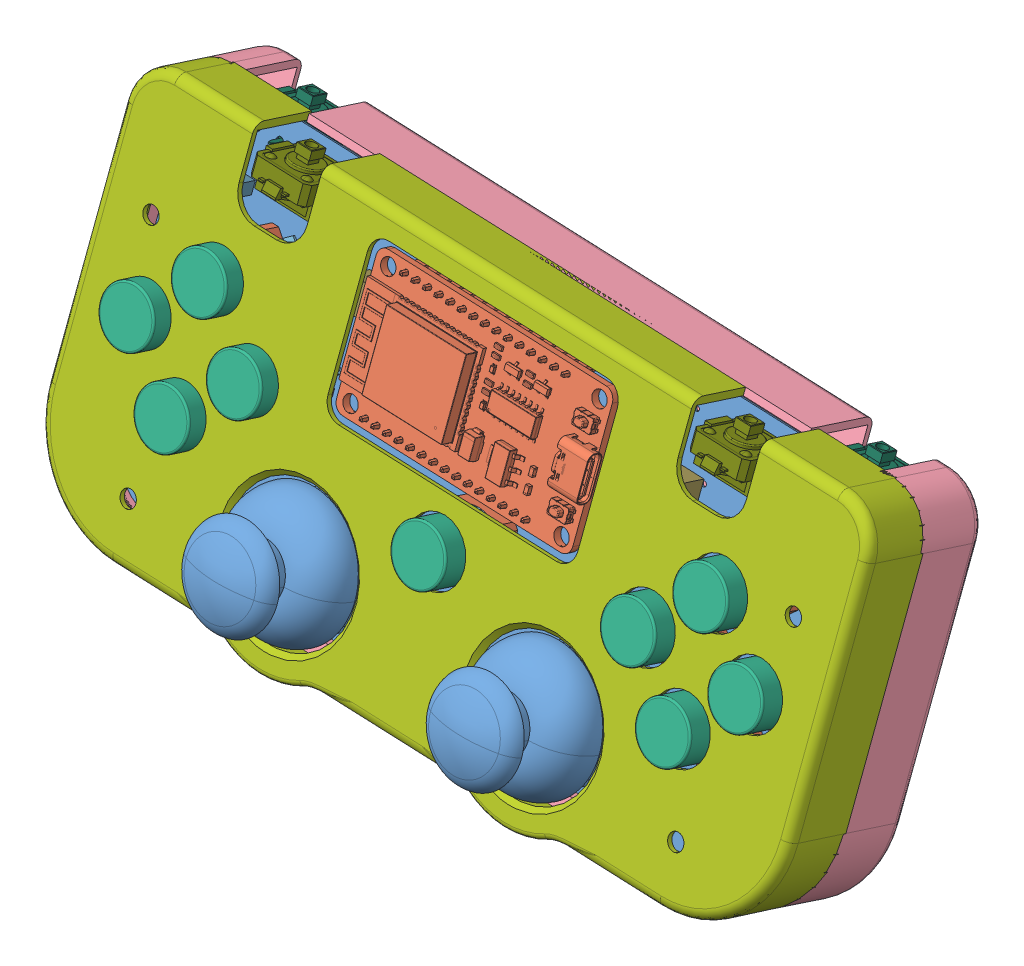
SolidWorks assembly controller, configuration Default. Lengths in mm.
Overall size (166.66 92.08 67.07).
209 component instances, 25 part files, 69 mates.
Components (placement in the parent):
- controller.step-1: controller.step [Default] at (25.4775 3.2443 108.305) x (0.999315 -0.03652 0.006033) z (0.005555 0.30909 0.951017) size (158.62 75.66 29.81)
  - Board.step-1: Board.step [Default] at origin size (158.62 74.17 0.41)
    - Open CASCADE STEP translator 7.5 1.1.1.step-1: Open CASCADE STEP translator 7.5 1.1.1.step [Default] at (0 0 -0.4115) size (158.62 74.17 0.41)
  - SW11.step-1: SW11.step [Default] at origin size (12 13.8 8.01)
    - Switch_Omron_B3F-4000_eec.step-1: Switch_Omron_B3F-4000_eec.step [Default] at (92.7295 35.2468 2.4624) x (0 1 0) z (0 0 1) size (13.8 12 8.01)
      - Omron B3F-4000 1.step-1: Omron B3F-4000 1.step [Default] at (3.1026 -5.4513 -0.4613) size (12 12 5.5)
      - Omron B3F-4000 2.step-1: Omron B3F-4000 2.step [Default] at (3.1026 -5.4513 2.5387) x (-1 0 0) z (0 0 1) size (11 11 0.5)
      - Omron B3F-4000 3.step-1: Omron B3F-4000 3.step [Default] at (3.1026 -5.4513 4.0387) x (1 0 0) z (0 0 -1) size (7.1 7.1 1.5)
      - Omron B3F-4000 4.step-1: Omron B3F-4000 4.step [Default] at (9.5526 -2.4513 -1.9613) x (1 0 0) z (0 -1 0) size (0.9 4 1)
      - Omron B3F-4000 4.step-2: Omron B3F-4000 4.step [Default] at (9.5526 -7.4513 -1.9613) x (1 0 0) z (0 -1 0) size (0.9 4 1)
      - Omron B3F-4000 4_MIR.step-1: Omron B3F-4000 4_MIR.step [Default] at (-3.3474 -2.4513 -1.9613) x (-1 0 0) z (0 1 0) size (0.9 4 1)
      - Omron B3F-4000 4_MIR.step-2: Omron B3F-4000 4_MIR.step [Default] at (-3.3474 -7.4513 -1.9613) x (-1 0 0) z (0 1 0) size (0.9 4 1)
      - Omron B3F-4000 5.step-1: Omron B3F-4000 5.step [Default] at (7.6026 -0.9513 3.0387) size (1.5 1.5 1.2)
      - Omron B3F-4000 5_MIR2.step-1: Omron B3F-4000 5_MIR2.step [Default] at (7.6026 -9.9513 3.0387) x (1 0 0) z (0 0 -1) size (1.5 1.5 1.2)
      - Omron B3F-4000 5_MIR3.step-1: Omron B3F-4000 5_MIR3.step [Default] at (-1.3974 -0.9513 3.0387) x (-1 0 0) z (0 0 -1) size (1.5 1.5 1.2)
      - Omron B3F-4000 5_MIR2_MIR.step-1: Omron B3F-4000 5_MIR2_MIR.step [Default] at (-1.3974 -9.9513 3.0387) x (-1 0 0) z (0 0 1) size (1.5 1.5 1.2)
      - Omron.step-1: Omron.step [Default] at (3.0502 -5.7952 4.0387) size (2.99 0.61 0.02)
  - SW9.step-1: SW9.step [Default] at origin size (6 6 4.5)
    - 7098939168.step-1: 7098939168.step [Default] at (64.389 64.262 0) size (6 6 4.5)
      - Extruded.step-1: Extruded.step [Default] at origin size (6 6 4.5)
  - SW10.step-1: SW10.step [Default] at origin size (6 6 4.5)
    - 7098939168.step-1: 7098939168.step [Default] at (131.953 64.262 0) size (6 6 4.5)
      - Extruded.step-1: Extruded.step [Default] at origin size (6 6 4.5)
  - C5.step-1: C5.step [Default] at origin size (3.81 2.54 11.66)
    - 7094425376.step-1: 7094425376.step [Default] at (34.6711 68.58 -7) size (0.51 0.51 7)
      - Extruded-0.step-1: Extruded-0.step [Default] at origin size (0.51 0.51 7)
    - 7094425376.step-2: 7094425376.step [Default] at (32.1311 68.5801 -7) size (0.51 0.51 7)
      - Extruded-0.step-1: Extruded-0.step [Default] at origin size (0.51 0.51 7)
    - 7098940608.step-1: 7098940608.step [Default] at (33.401 68.58 0) size (3.81 2.54 4.66)
      - Extruded-1.step-1: Extruded-1.step [Default] at origin size (3.81 2.54 4.66)
  - C6.step-1: C6.step [Default] at origin size (3.81 2.54 11.66)
    - 7094425376.step-1: 7094425376.step [Default] at (165.3541 67.31 -7) size (0.51 0.51 7)
      - Extruded-0.step-1: Extruded-0.step [Default] at origin size (0.51 0.51 7)
    - 7094425376.step-2: 7094425376.step [Default] at (162.8141 67.3101 -7) size (0.51 0.51 7)
      - Extruded-0.step-1: Extruded-0.step [Default] at origin size (0.51 0.51 7)
    - 7098940608.step-1: 7098940608.step [Default] at (164.084 67.31 0) size (3.81 2.54 4.66)
      - Extruded-1.step-1: Extruded-1.step [Default] at origin size (3.81 2.54 4.66)
  - S4.step-1: S4.step [Default] at origin size (13.1 13.3 18.3)
    - 6508629744.step-1: 6508629744.step [Default] at (160.742 77.978 -0.4115) x (0 -1 0) z (1 0 0) size (13.3 18.3 13.1)
  - S3.step-1: S3.step [Default] at origin size (13.1 13.3 18.3)
    - 6508631584.step-1: 6508631584.step [Default] at (146.344 77.978 0) x (0 -1 0) z (-1 0 0) size (13.3 18.3 13.1)
  - S2.step-1: S2.step [Default] at origin size (13.1 13.3 18.3)
    - 6508631584.step-1: 6508631584.step [Default] at (49.744 77.978 0) x (0 -1 0) z (-1 0 0) size (13.3 18.3 13.1)
  - S1.step-1: S1.step [Default] at origin size (13.1 13.3 18.3)
    - 6508629744.step-1: 6508629744.step [Default] at (35.346 77.978 -0.4115) x (0 -1 0) z (1 0 0) size (13.3 18.3 13.1)
  - C4.step-1: C4.step [Default] at origin size (4.49 4.49 11.66)
    - 7094425376.step-1: 7094425376.step [Default] at (30.4371 33.138 -7) size (0.51 0.51 7)
      - Extruded-0.step-1: Extruded-0.step [Default] at origin size (0.51 0.51 7)
    - 7094425376.step-2: 7094425376.step [Default] at (28.6411 34.9341 -7) size (0.51 0.51 7)
      - Extruded-0.step-1: Extruded-0.step [Default] at origin size (0.51 0.51 7)
    - 7094424896.step-1: 7094424896.step [Default] at (29.5392 34.036 0) size (4.49 4.49 4.66)
      - Extruded-2.step-1: Extruded-2.step [Default] at origin size (4.49 4.49 4.66)
  - C3.step-1: C3.step [Default] at origin size (4.49 4.49 11.66)
    - 7094425376.step-1: 7094425376.step [Default] at (166.7082 33.9179 -7) size (0.51 0.51 7)
      - Extruded-0.step-1: Extruded-0.step [Default] at origin size (0.51 0.51 7)
    - 7094425376.step-2: 7094425376.step [Default] at (164.9122 32.1219 -7) size (0.51 0.51 7)
      - Extruded-0.step-1: Extruded-0.step [Default] at origin size (0.51 0.51 7)
    - 7098938768.step-1: 7098938768.step [Default] at (165.8102 33.02 0) size (4.49 4.49 4.66)
      - Extruded-3.step-1: Extruded-3.step [Default] at origin size (4.49 4.49 4.66)
  - C2.step-1: C2.step [Default] at origin size (4.49 4.49 11.66)
    - 7094425376.step-1: 7094425376.step [Default] at (55.4293 60.9781 -7) size (0.51 0.51 7)
      - Extruded-0.step-1: Extruded-0.step [Default] at origin size (0.51 0.51 7)
    - 7094425376.step-2: 7094425376.step [Default] at (57.2253 59.182 -7) size (0.51 0.51 7)
      - Extruded-0.step-1: Extruded-0.step [Default] at origin size (0.51 0.51 7)
    - 7094424896.step-1: 7094424896.step [Default] at (56.3272 60.08 0) size (4.49 4.49 4.66)
      - Extruded-2.step-1: Extruded-2.step [Default] at origin size (4.49 4.49 4.66)
  - C1.step-1: C1.step [Default] at origin size (4.49 4.49 11.66)
    - 7094425376.step-1: 7094425376.step [Default] at (139.5122 58.4111 -7) size (0.51 0.51 7)
      - Extruded-0.step-1: Extruded-0.step [Default] at origin size (0.51 0.51 7)
    - 7094425376.step-2: 7094425376.step [Default] at (141.3083 60.2071 -7) size (0.51 0.51 7)
      - Extruded-0.step-1: Extruded-0.step [Default] at origin size (0.51 0.51 7)
    - 7098938768.step-1: 7098938768.step [Default] at (140.4102 59.309 0) size (4.49 4.49 4.66)
      - Extruded-3.step-1: Extruded-3.step [Default] at origin size (4.49 4.49 4.66)
  - SW1.step-1: SW1.step [Default] at origin size (18.24 18.24 8.01)
    - Switch_Omron_B3F-4000_eec.step-1: Switch_Omron_B3F-4000_eec.step [Default] at (48.6404 48.2596 2.4624) x (0.707107 0.707107 0) z (0 0 1) size (13.8 12 8.01)
      - Omron B3F-4000 1.step-1: Omron B3F-4000 1.step [Default] at (3.1026 -5.4513 -0.4613) size (12 12 5.5)
      - Omron B3F-4000 2.step-1: Omron B3F-4000 2.step [Default] at (3.1026 -5.4513 2.5387) x (-1 0 0) z (0 0 1) size (11 11 0.5)
      - Omron B3F-4000 3.step-1: Omron B3F-4000 3.step [Default] at (3.1026 -5.4513 4.0387) x (1 0 0) z (0 0 -1) size (7.1 7.1 1.5)
      - Omron B3F-4000 4.step-1: Omron B3F-4000 4.step [Default] at (9.5526 -2.4513 -1.9613) x (1 0 0) z (0 -1 0) size (0.9 4 1)
      - Omron B3F-4000 4.step-2: Omron B3F-4000 4.step [Default] at (9.5526 -7.4513 -1.9613) x (1 0 0) z (0 -1 0) size (0.9 4 1)
      - Omron B3F-4000 4_MIR.step-1: Omron B3F-4000 4_MIR.step [Default] at (-3.3474 -2.4513 -1.9613) x (-1 0 0) z (0 1 0) size (0.9 4 1)
      - Omron B3F-4000 4_MIR.step-2: Omron B3F-4000 4_MIR.step [Default] at (-3.3474 -7.4513 -1.9613) x (-1 0 0) z (0 1 0) size (0.9 4 1)
      - Omron B3F-4000 5.step-1: Omron B3F-4000 5.step [Default] at (7.6026 -0.9513 3.0387) size (1.5 1.5 1.2)
      - Omron B3F-4000 5_MIR2.step-1: Omron B3F-4000 5_MIR2.step [Default] at (7.6026 -9.9513 3.0387) x (1 0 0) z (0 0 -1) size (1.5 1.5 1.2)
      - Omron B3F-4000 5_MIR3.step-1: Omron B3F-4000 5_MIR3.step [Default] at (-1.3974 -0.9513 3.0387) x (-1 0 0) z (0 0 -1) size (1.5 1.5 1.2)
      - Omron B3F-4000 5_MIR2_MIR.step-1: Omron B3F-4000 5_MIR2_MIR.step [Default] at (-1.3974 -9.9513 3.0387) x (-1 0 0) z (0 0 1) size (1.5 1.5 1.2)
      - Omron.step-1: Omron.step [Default] at (3.0502 -5.7952 4.0387) size (2.99 0.61 0.02)
  - SW2.step-1: SW2.step [Default] at origin size (18.24 18.24 8.01)
    - Switch_Omron_B3F-4000_eec.step-1: Switch_Omron_B3F-4000_eec.step [Default] at (36.8294 60.0706 2.4624) x (0.707107 0.707107 0) z (0 0 1) size (13.8 12 8.01)
      - Omron B3F-4000 1.step-1: Omron B3F-4000 1.step [Default] at (3.1026 -5.4513 -0.4613) size (12 12 5.5)
      - Omron B3F-4000 2.step-1: Omron B3F-4000 2.step [Default] at (3.1026 -5.4513 2.5387) x (-1 0 0) z (0 0 1) size (11 11 0.5)
      - Omron B3F-4000 3.step-1: Omron B3F-4000 3.step [Default] at (3.1026 -5.4513 4.0387) x (1 0 0) z (0 0 -1) size (7.1 7.1 1.5)
      - Omron B3F-4000 4.step-1: Omron B3F-4000 4.step [Default] at (9.5526 -2.4513 -1.9613) x (1 0 0) z (0 -1 0) size (0.9 4 1)
      - Omron B3F-4000 4.step-2: Omron B3F-4000 4.step [Default] at (9.5526 -7.4513 -1.9613) x (1 0 0) z (0 -1 0) size (0.9 4 1)
      - Omron B3F-4000 4_MIR.step-1: Omron B3F-4000 4_MIR.step [Default] at (-3.3474 -2.4513 -1.9613) x (-1 0 0) z (0 1 0) size (0.9 4 1)
      - Omron B3F-4000 4_MIR.step-2: Omron B3F-4000 4_MIR.step [Default] at (-3.3474 -7.4513 -1.9613) x (-1 0 0) z (0 1 0) size (0.9 4 1)
      - Omron B3F-4000 5.step-1: Omron B3F-4000 5.step [Default] at (7.6026 -0.9513 3.0387) size (1.5 1.5 1.2)
      - Omron B3F-4000 5_MIR2.step-1: Omron B3F-4000 5_MIR2.step [Default] at (7.6026 -9.9513 3.0387) x (1 0 0) z (0 0 -1) size (1.5 1.5 1.2)
      - Omron B3F-4000 5_MIR3.step-1: Omron B3F-4000 5_MIR3.step [Default] at (-1.3974 -0.9513 3.0387) x (-1 0 0) z (0 0 -1) size (1.5 1.5 1.2)
      - Omron B3F-4000 5_MIR2_MIR.step-1: Omron B3F-4000 5_MIR2_MIR.step [Default] at (-1.3974 -9.9513 3.0387) x (-1 0 0) z (0 0 1) size (1.5 1.5 1.2)
      - Omron.step-1: Omron.step [Default] at (3.0502 -5.7952 4.0387) size (2.99 0.61 0.02)
  - SW3.step-1: SW3.step [Default] at origin size (18.24 18.24 8.01)
    - Switch_Omron_B3F-4000_eec.step-1: Switch_Omron_B3F-4000_eec.step [Default] at (25.0184 48.2596 2.4624) x (0.707107 0.707107 0) z (0 0 1) size (13.8 12 8.01)
      - Omron B3F-4000 1.step-1: Omron B3F-4000 1.step [Default] at (3.1026 -5.4513 -0.4613) size (12 12 5.5)
      - Omron B3F-4000 2.step-1: Omron B3F-4000 2.step [Default] at (3.1026 -5.4513 2.5387) x (-1 0 0) z (0 0 1) size (11 11 0.5)
      - Omron B3F-4000 3.step-1: Omron B3F-4000 3.step [Default] at (3.1026 -5.4513 4.0387) x (1 0 0) z (0 0 -1) size (7.1 7.1 1.5)
      - Omron B3F-4000 4.step-1: Omron B3F-4000 4.step [Default] at (9.5526 -2.4513 -1.9613) x (1 0 0) z (0 -1 0) size (0.9 4 1)
      - Omron B3F-4000 4.step-2: Omron B3F-4000 4.step [Default] at (9.5526 -7.4513 -1.9613) x (1 0 0) z (0 -1 0) size (0.9 4 1)
      - Omron B3F-4000 4_MIR.step-1: Omron B3F-4000 4_MIR.step [Default] at (-3.3474 -2.4513 -1.9613) x (-1 0 0) z (0 1 0) size (0.9 4 1)
      - Omron B3F-4000 4_MIR.step-2: Omron B3F-4000 4_MIR.step [Default] at (-3.3474 -7.4513 -1.9613) x (-1 0 0) z (0 1 0) size (0.9 4 1)
      - Omron B3F-4000 5.step-1: Omron B3F-4000 5.step [Default] at (7.6026 -0.9513 3.0387) size (1.5 1.5 1.2)
      - Omron B3F-4000 5_MIR2.step-1: Omron B3F-4000 5_MIR2.step [Default] at (7.6026 -9.9513 3.0387) x (1 0 0) z (0 0 -1) size (1.5 1.5 1.2)
      - Omron B3F-4000 5_MIR3.step-1: Omron B3F-4000 5_MIR3.step [Default] at (-1.3974 -0.9513 3.0387) x (-1 0 0) z (0 0 -1) size (1.5 1.5 1.2)
      - Omron B3F-4000 5_MIR2_MIR.step-1: Omron B3F-4000 5_MIR2_MIR.step [Default] at (-1.3974 -9.9513 3.0387) x (-1 0 0) z (0 0 1) size (1.5 1.5 1.2)
      - Omron.step-1: Omron.step [Default] at (3.0502 -5.7952 4.0387) size (2.99 0.61 0.02)
  - SW4.step-1: SW4.step [Default] at origin size (18.24 18.24 8.01)
    - Switch_Omron_B3F-4000_eec.step-1: Switch_Omron_B3F-4000_eec.step [Default] at (36.8294 36.4486 2.4624) x (0.707107 0.707107 0) z (0 0 1) size (13.8 12 8.01)
      - Omron B3F-4000 1.step-1: Omron B3F-4000 1.step [Default] at (3.1026 -5.4513 -0.4613) size (12 12 5.5)
      - Omron B3F-4000 2.step-1: Omron B3F-4000 2.step [Default] at (3.1026 -5.4513 2.5387) x (-1 0 0) z (0 0 1) size (11 11 0.5)
      - Omron B3F-4000 3.step-1: Omron B3F-4000 3.step [Default] at (3.1026 -5.4513 4.0387) x (1 0 0) z (0 0 -1) size (7.1 7.1 1.5)
      - Omron B3F-4000 4.step-1: Omron B3F-4000 4.step [Default] at (9.5526 -2.4513 -1.9613) x (1 0 0) z (0 -1 0) size (0.9 4 1)
      - Omron B3F-4000 4.step-2: Omron B3F-4000 4.step [Default] at (9.5526 -7.4513 -1.9613) x (1 0 0) z (0 -1 0) size (0.9 4 1)
      - Omron B3F-4000 4_MIR.step-1: Omron B3F-4000 4_MIR.step [Default] at (-3.3474 -2.4513 -1.9613) x (-1 0 0) z (0 1 0) size (0.9 4 1)
      - Omron B3F-4000 4_MIR.step-2: Omron B3F-4000 4_MIR.step [Default] at (-3.3474 -7.4513 -1.9613) x (-1 0 0) z (0 1 0) size (0.9 4 1)
      - Omron B3F-4000 5.step-1: Omron B3F-4000 5.step [Default] at (7.6026 -0.9513 3.0387) size (1.5 1.5 1.2)
      - Omron B3F-4000 5_MIR2.step-1: Omron B3F-4000 5_MIR2.step [Default] at (7.6026 -9.9513 3.0387) x (1 0 0) z (0 0 -1) size (1.5 1.5 1.2)
      - Omron B3F-4000 5_MIR3.step-1: Omron B3F-4000 5_MIR3.step [Default] at (-1.3974 -0.9513 3.0387) x (-1 0 0) z (0 0 -1) size (1.5 1.5 1.2)
      - Omron B3F-4000 5_MIR2_MIR.step-1: Omron B3F-4000 5_MIR2_MIR.step [Default] at (-1.3974 -9.9513 3.0387) x (-1 0 0) z (0 0 1) size (1.5 1.5 1.2)
      - Omron.step-1: Omron.step [Default] at (3.0502 -5.7952 4.0387) size (2.99 0.61 0.02)
  - SW8.step-1: SW8.step [Default] at origin size (18.24 18.24 8.01)
    - Switch_Omron_B3F-4000_eec.step-1: Switch_Omron_B3F-4000_eec.step [Default] at (147.1924 36.4486 2.4624) x (0.707107 0.707107 0) z (0 0 1) size (13.8 12 8.01)
      - Omron B3F-4000 1.step-1: Omron B3F-4000 1.step [Default] at (3.1026 -5.4513 -0.4613) size (12 12 5.5)
      - Omron B3F-4000 2.step-1: Omron B3F-4000 2.step [Default] at (3.1026 -5.4513 2.5387) x (-1 0 0) z (0 0 1) size (11 11 0.5)
      - Omron B3F-4000 3.step-1: Omron B3F-4000 3.step [Default] at (3.1026 -5.4513 4.0387) x (1 0 0) z (0 0 -1) size (7.1 7.1 1.5)
      - Omron B3F-4000 4.step-1: Omron B3F-4000 4.step [Default] at (9.5526 -2.4513 -1.9613) x (1 0 0) z (0 -1 0) size (0.9 4 1)
      - Omron B3F-4000 4.step-2: Omron B3F-4000 4.step [Default] at (9.5526 -7.4513 -1.9613) x (1 0 0) z (0 -1 0) size (0.9 4 1)
      - Omron B3F-4000 4_MIR.step-1: Omron B3F-4000 4_MIR.step [Default] at (-3.3474 -2.4513 -1.9613) x (-1 0 0) z (0 1 0) size (0.9 4 1)
      - Omron B3F-4000 4_MIR.step-2: Omron B3F-4000 4_MIR.step [Default] at (-3.3474 -7.4513 -1.9613) x (-1 0 0) z (0 1 0) size (0.9 4 1)
      - Omron B3F-4000 5.step-1: Omron B3F-4000 5.step [Default] at (7.6026 -0.9513 3.0387) size (1.5 1.5 1.2)
      - Omron B3F-4000 5_MIR2.step-1: Omron B3F-4000 5_MIR2.step [Default] at (7.6026 -9.9513 3.0387) x (1 0 0) z (0 0 -1) size (1.5 1.5 1.2)
      - Omron B3F-4000 5_MIR3.step-1: Omron B3F-4000 5_MIR3.step [Default] at (-1.3974 -0.9513 3.0387) x (-1 0 0) z (0 0 -1) size (1.5 1.5 1.2)
      - Omron B3F-4000 5_MIR2_MIR.step-1: Omron B3F-4000 5_MIR2_MIR.step [Default] at (-1.3974 -9.9513 3.0387) x (-1 0 0) z (0 0 1) size (1.5 1.5 1.2)
      - Omron.step-1: Omron.step [Default] at (3.0502 -5.7952 4.0387) size (2.99 0.61 0.02)
  - SW7.step-1: SW7.step [Default] at origin size (18.24 18.24 8.01)
    - Switch_Omron_B3F-4000_eec.step-1: Switch_Omron_B3F-4000_eec.step [Default] at (135.3813 48.2596 2.4624) x (0.707107 0.707107 0) z (0 0 1) size (13.8 12 8.01)
      - Omron B3F-4000 1.step-1: Omron B3F-4000 1.step [Default] at (3.1026 -5.4513 -0.4613) size (12 12 5.5)
      - Omron B3F-4000 2.step-1: Omron B3F-4000 2.step [Default] at (3.1026 -5.4513 2.5387) x (-1 0 0) z (0 0 1) size (11 11 0.5)
      - Omron B3F-4000 3.step-1: Omron B3F-4000 3.step [Default] at (3.1026 -5.4513 4.0387) x (1 0 0) z (0 0 -1) size (7.1 7.1 1.5)
      - Omron B3F-4000 4.step-1: Omron B3F-4000 4.step [Default] at (9.5526 -2.4513 -1.9613) x (1 0 0) z (0 -1 0) size (0.9 4 1)
      - Omron B3F-4000 4.step-2: Omron B3F-4000 4.step [Default] at (9.5526 -7.4513 -1.9613) x (1 0 0) z (0 -1 0) size (0.9 4 1)
      - Omron B3F-4000 4_MIR.step-1: Omron B3F-4000 4_MIR.step [Default] at (-3.3474 -2.4513 -1.9613) x (-1 0 0) z (0 1 0) size (0.9 4 1)
      - Omron B3F-4000 4_MIR.step-2: Omron B3F-4000 4_MIR.step [Default] at (-3.3474 -7.4513 -1.9613) x (-1 0 0) z (0 1 0) size (0.9 4 1)
      - Omron B3F-4000 5.step-1: Omron B3F-4000 5.step [Default] at (7.6026 -0.9513 3.0387) size (1.5 1.5 1.2)
      - Omron B3F-4000 5_MIR2.step-1: Omron B3F-4000 5_MIR2.step [Default] at (7.6026 -9.9513 3.0387) x (1 0 0) z (0 0 -1) size (1.5 1.5 1.2)
      - Omron B3F-4000 5_MIR3.step-1: Omron B3F-4000 5_MIR3.step [Default] at (-1.3974 -0.9513 3.0387) x (-1 0 0) z (0 0 -1) size (1.5 1.5 1.2)
      - Omron B3F-4000 5_MIR2_MIR.step-1: Omron B3F-4000 5_MIR2_MIR.step [Default] at (-1.3974 -9.9513 3.0387) x (-1 0 0) z (0 0 1) size (1.5 1.5 1.2)
      - Omron.step-1: Omron.step [Default] at (3.0502 -5.7952 4.0387) size (2.99 0.61 0.02)
  - SW6.step-1: SW6.step [Default] at origin size (18.24 18.24 8.01)
    - Switch_Omron_B3F-4000_eec.step-1: Switch_Omron_B3F-4000_eec.step [Default] at (147.1924 60.0706 2.4624) x (0.707107 0.707107 0) z (0 0 1) size (13.8 12 8.01)
      - Omron B3F-4000 1.step-1: Omron B3F-4000 1.step [Default] at (3.1026 -5.4513 -0.4613) size (12 12 5.5)
      - Omron B3F-4000 2.step-1: Omron B3F-4000 2.step [Default] at (3.1026 -5.4513 2.5387) x (-1 0 0) z (0 0 1) size (11 11 0.5)
      - Omron B3F-4000 3.step-1: Omron B3F-4000 3.step [Default] at (3.1026 -5.4513 4.0387) x (1 0 0) z (0 0 -1) size (7.1 7.1 1.5)
      - Omron B3F-4000 4.step-1: Omron B3F-4000 4.step [Default] at (9.5526 -2.4513 -1.9613) x (1 0 0) z (0 -1 0) size (0.9 4 1)
      - Omron B3F-4000 4.step-2: Omron B3F-4000 4.step [Default] at (9.5526 -7.4513 -1.9613) x (1 0 0) z (0 -1 0) size (0.9 4 1)
      - Omron B3F-4000 4_MIR.step-1: Omron B3F-4000 4_MIR.step [Default] at (-3.3474 -2.4513 -1.9613) x (-1 0 0) z (0 1 0) size (0.9 4 1)
      - Omron B3F-4000 4_MIR.step-2: Omron B3F-4000 4_MIR.step [Default] at (-3.3474 -7.4513 -1.9613) x (-1 0 0) z (0 1 0) size (0.9 4 1)
      - Omron B3F-4000 5.step-1: Omron B3F-4000 5.step [Default] at (7.6026 -0.9513 3.0387) size (1.5 1.5 1.2)
      - Omron B3F-4000 5_MIR2.step-1: Omron B3F-4000 5_MIR2.step [Default] at (7.6026 -9.9513 3.0387) x (1 0 0) z (0 0 -1) size (1.5 1.5 1.2)
      - Omron B3F-4000 5_MIR3.step-1: Omron B3F-4000 5_MIR3.step [Default] at (-1.3974 -0.9513 3.0387) x (-1 0 0) z (0 0 -1) size (1.5 1.5 1.2)
      - Omron B3F-4000 5_MIR2_MIR.step-1: Omron B3F-4000 5_MIR2_MIR.step [Default] at (-1.3974 -9.9513 3.0387) x (-1 0 0) z (0 0 1) size (1.5 1.5 1.2)
      - Omron.step-1: Omron.step [Default] at (3.0502 -5.7952 4.0387) size (2.99 0.61 0.02)
  - SW5.step-1: SW5.step [Default] at origin size (18.24 18.24 8.01)
    - Switch_Omron_B3F-4000_eec.step-1: Switch_Omron_B3F-4000_eec.step [Default] at (159.0034 48.2596 2.4624) x (0.707107 0.707107 0) z (0 0 1) size (13.8 12 8.01)
      - Omron B3F-4000 1.step-1: Omron B3F-4000 1.step [Default] at (3.1026 -5.4513 -0.4613) size (12 12 5.5)
      - Omron B3F-4000 2.step-1: Omron B3F-4000 2.step [Default] at (3.1026 -5.4513 2.5387) x (-1 0 0) z (0 0 1) size (11 11 0.5)
      - Omron B3F-4000 3.step-1: Omron B3F-4000 3.step [Default] at (3.1026 -5.4513 4.0387) x (1 0 0) z (0 0 -1) size (7.1 7.1 1.5)
      - Omron B3F-4000 4.step-1: Omron B3F-4000 4.step [Default] at (9.5526 -2.4513 -1.9613) x (1 0 0) z (0 -1 0) size (0.9 4 1)
      - Omron B3F-4000 4.step-2: Omron B3F-4000 4.step [Default] at (9.5526 -7.4513 -1.9613) x (1 0 0) z (0 -1 0) size (0.9 4 1)
      - Omron B3F-4000 4_MIR.step-1: Omron B3F-4000 4_MIR.step [Default] at (-3.3474 -2.4513 -1.9613) x (-1 0 0) z (0 1 0) size (0.9 4 1)
      - Omron B3F-4000 4_MIR.step-2: Omron B3F-4000 4_MIR.step [Default] at (-3.3474 -7.4513 -1.9613) x (-1 0 0) z (0 1 0) size (0.9 4 1)
      - Omron B3F-4000 5.step-1: Omron B3F-4000 5.step [Default] at (7.6026 -0.9513 3.0387) size (1.5 1.5 1.2)
      - Omron B3F-4000 5_MIR2.step-1: Omron B3F-4000 5_MIR2.step [Default] at (7.6026 -9.9513 3.0387) x (1 0 0) z (0 0 -1) size (1.5 1.5 1.2)
      - Omron B3F-4000 5_MIR3.step-1: Omron B3F-4000 5_MIR3.step [Default] at (-1.3974 -0.9513 3.0387) x (-1 0 0) z (0 0 -1) size (1.5 1.5 1.2)
      - Omron B3F-4000 5_MIR2_MIR.step-1: Omron B3F-4000 5_MIR2_MIR.step [Default] at (-1.3974 -9.9513 3.0387) x (-1 0 0) z (0 0 1) size (1.5 1.5 1.2)
      - Omron.step-1: Omron.step [Default] at (3.0502 -5.7952 4.0387) size (2.99 0.61 0.02)
- COM-09032-1: COM-09032 [Default] at (97.4277 22.5889 101.5976) x (0.999315 -0.03652 0.006033) z (-0.036596 -0.950331 0.309081) size (26.67 34.67 27.62)
- COM-09032-2: COM-09032 [Default] at (151.2136 20.6099 101.9266) x (0.999315 -0.03652 0.006033) z (-0.036596 -0.950331 0.309081) size (26.67 34.67 27.62)
- esp32_30pin-1: esp32_30pin [По умолчанию] at (148.2005 52.2986 104.8892) x (0.036596 0.950331 -0.309081) z (0.005555 0.30909 0.951017) size (29 52.96 13.53)
- powerboost 1000c.f3d v3-1: powerboost 1000c.f3d v3 [Default] at (151.8493 9.8112 109.6265) x (0.036596 0.950331 -0.309081) z (-0.005555 -0.30909 -0.951017) size (36.64 22.86 4.38)
- Part1-1: Part1 [Default] at (45.204 24.8437 87.0675) x (0.999315 -0.03652 0.006033) z (-0.036596 -0.950331 0.309081) size (163.63 14.65 81.83)
- 12mm Push Button Cap-1: 12mm Push Button Cap [Default] at (179.9154 32.315 103.4225) x (0.640311 -0.731594 0.234035) z (-0.768096 -0.607647 0.201977) size (13 8.2 13)
- 12mm Push Button Cap-2: 12mm Push Button Cap [Default] at (180.7799 54.7638 96.1214) x (0.640311 -0.731594 0.234035) z (-0.768096 -0.607647 0.201977) size (13 8.2 13)
- 12mm Push Button Cap-3: 12mm Push Button Cap [Default] at (168.5447 43.9708 99.7007) x (0.640311 -0.731594 0.234035) z (-0.768096 -0.607647 0.201977) size (13 8.2 13)
- 12mm Push Button Cap-4: 12mm Push Button Cap [Default] at (192.1505 43.1081 99.8432) x (0.191146 0.933167 -0.304405) z (0.981546 -0.183474 0.053898) size (13 8.2 13)
- 12mm Push Button Cap-5: 12mm Push Button Cap [Default] at (125.0234 37.7106 101.9895) x (0.640311 -0.731594 0.234035) z (-0.768096 -0.607647 0.201977) size (13 8.2 13)
- 12mm Push Button Cap TALL-1: 12mm Push Button Cap TALL [Default] at (192.1505 43.1081 99.8432) x (-0.613772 -0.749763 0.247265) z (-0.789464 0.585081 -0.185546) size (13 14.2 13)
- top_plate-1: top_plate [Default] at (203.8676 27.2141 113.1422) x (-0.999315 0.03652 -0.006033) z (-0.036596 -0.950331 0.309081) size (163.63 13.51 81.83)
- 12mm Push Button Cap-6: 12mm Push Button Cap [Default] at (58.2574 48.0013 99.0349) x (0.7195 -0.661708 0.210859) z (-0.69447 -0.683086 0.226066) size (13 8.2 13)
- 12mm Push Button Cap-7: 12mm Push Button Cap [Default] at (70.4925 58.7943 95.4556) x (0.640311 -0.731594 0.234035) z (-0.768096 -0.607647 0.201977) size (13 8.2 13)
- 12mm Push Button Cap-8: 12mm Push Button Cap [Default] at (69.628 36.3456 102.7567) x (0.640311 -0.731594 0.234035) z (-0.768096 -0.607647 0.201977) size (13 8.2 13)
- 12mm Push Button Cap-9: 12mm Push Button Cap [Default] at (81.8632 47.1386 99.1774) x (0.640311 -0.731594 0.234035) z (-0.768096 -0.607647 0.201977) size (13 8.2 13)
- 12mm Push Button Cap TALL-6: 12mm Push Button Cap TALL [Default] at (180.7799 54.7638 96.1214) x (-0.999145 0.040688 -0.007388) z (0.040979 0.950162 -0.309051) size (13 14.2 13)
- 12mm Push Button Cap TALL-7: 12mm Push Button Cap TALL [Default] at (125.0234 37.7106 101.9895) x (-0.613772 -0.749763 0.247265) z (-0.789464 0.585081 -0.185546) size (13 14.2 13)
- 12mm Push Button Cap TALL-8: 12mm Push Button Cap TALL [Default] at (58.2574 48.0013 99.0349) x (-0.502403 -0.821427 0.269906) z (-0.864616 0.479293 -0.150725) size (13 14.2 13)
- 12mm Push Button Cap TALL-9: 12mm Push Button Cap TALL [Default] at (69.628 36.3456 102.7567) x (-0.776873 -0.597476 0.198723) z (-0.629633 0.739923 -0.236805) size (13 14.2 13)
- 12mm Push Button Cap TALL-10: 12mm Push Button Cap TALL [Default] at (168.5447 43.9708 99.7007) x (-0.613772 -0.749763 0.247265) z (-0.789464 0.585081 -0.185546) size (13 14.2 13)
- 12mm Push Button Cap TALL-11: 12mm Push Button Cap TALL [Default] at (179.9154 32.315 103.4225) x (-0.613772 -0.749763 0.247265) z (-0.789464 0.585081 -0.185546) size (13 14.2 13)
- 12mm Push Button Cap TALL-12: 12mm Push Button Cap TALL [Default] at (70.4925 58.7943 95.4556) x (-0.78112 -0.592451 0.197115) z (-0.624357 0.743953 -0.238145) size (13 14.2 13)
- 12mm Push Button Cap TALL-13: 12mm Push Button Cap TALL [Default] at (81.8632 47.1386 99.1774) x (-0.613772 -0.749763 0.247265) z (-0.789464 0.585081 -0.185546) size (13 14.2 13)
Mates (geometry in assembly coordinates):
- Coincident2: coincident anti-aligned: plane of controller.step-1/Board.step-1/Open CASCADE STEP translator 7.5 1.1.1.step-1 through (125.235 44.2553 94.3933) normal (0.005555 0.30909 0.951017); plane of COM-09032-1 through (97.4277 22.5889 101.5976) normal (-0.005555 -0.30909 -0.951017)
- Parallel6: parallel aligned: plane of controller.step-1/Board.step-1/Open CASCADE STEP translator 7.5 1.1.1.step-1 through (184.0564 5.6611 106.1606) normal (-0.036596 -0.950331 0.309081); plane of COM-09032-1 through (96.5277 11.5931 105.1766) normal (-0.036596 -0.950331 0.309081)
- Distance1: distance = 2.7383 mm aligned: plane of COM-09032-1 through (96.5277 11.5931 105.1766) normal (-0.036596 -0.950331 0.309081); plane of controller.step-1/Board.step-1/Open CASCADE STEP translator 7.5 1.1.1.step-1 through (184.0564 5.6611 106.1606) normal (-0.036596 -0.950331 0.309081)
- Distance3: distance = 44.4205 mm aligned: plane of COM-09032-1 through (89.0631 7.9437 82.7993) normal (-0.999315 0.03652 -0.006033); plane of controller.step-1/Board.step-1/Open CASCADE STEP translator 7.5 1.1.1.step-1 through (45.2762 28.8622 99.4306) normal (-0.999315 0.03652 -0.006033)
- Coincident17: coincident anti-aligned: plane of controller.step-1/Board.step-1/Open CASCADE STEP translator 7.5 1.1.1.step-1 through (125.235 44.2553 94.3933) normal (0.005555 0.30909 0.951017); plane of COM-09032-2 through (151.2136 20.6099 101.9266) normal (-0.005555 -0.30909 -0.951017)
- Parallel8: parallel: line of controller.step-1/Board.step-1/Open CASCADE STEP translator 7.5 1.1.1.step-1 through (184.0564 5.6611 106.1606) axis (-0.999315 0.03652 -0.006033); plane of COM-09032-2 through (150.3136 9.6141 105.5056) normal (-0.036596 -0.950331 0.309081)
- Distance4: distance = 44.5042 mm aligned: plane of COM-09032-2 through (158.7131 5.3849 83.2241) normal (0.999315 -0.03652 0.006033); plane of controller.step-1/Board.step-1/Open CASCADE STEP translator 7.5 1.1.1.step-1 through (205.5752 69.415 85.3143) normal (0.999315 -0.03652 0.006033)
- Distance5: distance = 2.7243 mm aligned: plane of COM-09032-2 through (150.3136 9.6141 105.5056) normal (-0.036596 -0.950331 0.309081); plane of controller.step-1/Board.step-1/Open CASCADE STEP translator 7.5 1.1.1.step-1 through (184.0564 5.6611 106.1606) normal (-0.036596 -0.950331 0.309081)
- Parallel9: parallel anti-aligned: plane of controller.step-1/Board.step-1/Open CASCADE STEP translator 7.5 1.1.1.step-1 through (125.235 44.2553 94.3933) normal (0.005555 0.30909 0.951017); plane of esp32_30pin-1 through (125.2811 64.1247 99.5019) normal (-0.005555 -0.30909 -0.951017)
- Parallel10: parallel aligned: plane of controller.step-1/Board.step-1/Open CASCADE STEP translator 7.5 1.1.1.step-1 through (53.639 81.0107 82.433) normal (0.036596 0.950331 -0.309081); plane of esp32_30pin-1 through (149.7954 77.028 95.165) normal (0.036596 0.950331 -0.309081)
- Parallel11: parallel aligned: plane of controller.step-1/Board.step-1/Open CASCADE STEP translator 7.5 1.1.1.step-1 through (45.2762 28.8622 99.4306) normal (-0.999315 0.03652 -0.006033); plane of esp32_30pin-1 through (99.7565 76.9533 95.4816) normal (-0.999315 0.03652 -0.006033)
- Distance10: distance = 53.9602 mm aligned: plane of esp32_30pin-1 through (150.8059 51.296 103.5223) normal (0.999315 -0.03652 0.006033); plane of controller.step-1/Board.step-1/Open CASCADE STEP translator 7.5 1.1.1.step-1 through (205.5752 69.415 85.3143) normal (0.999315 -0.03652 0.006033)
- Distance11: distance = 4.2011 mm aligned: plane of esp32_30pin-1 through (149.7954 77.028 95.165) normal (0.036596 0.950331 -0.309081); plane of controller.step-1/Board.step-1/Open CASCADE STEP translator 7.5 1.1.1.step-1 through (53.639 81.0107 82.433) normal (0.036596 0.950331 -0.309081)
- Parallel15: parallel aligned: plane of controller.step-1/Board.step-1/Open CASCADE STEP translator 7.5 1.1.1.step-1 through (125.2328 44.1282 94.002) normal (-0.005555 -0.30909 -0.951017); plane of powerboost 1000c.f3d v3-1 through (124.3289 22.2845 91.0122) normal (-0.005555 -0.30909 -0.951017)
- Parallel18: parallel aligned: plane of controller.step-1/Board.step-1/Open CASCADE STEP translator 7.5 1.1.1.step-1 through (184.0564 5.6611 106.1606) normal (-0.036596 -0.950331 0.309081); plane of powerboost 1000c.f3d v3-1 through (135.0976 5.1606 98.1972) normal (-0.036596 -0.950331 0.309081)
- Distance13: distance = 11 mm anti-aligned: plane of esp32_30pin-1 through (125.2811 64.1247 99.5019) normal (-0.005555 -0.30909 -0.951017); plane of controller.step-1/Board.step-1/Open CASCADE STEP translator 7.5 1.1.1.step-1 through (125.235 44.2553 94.3933) normal (0.005555 0.30909 0.951017)
- Parallel19: parallel anti-aligned: plane of controller.step-1/Board.step-1/Open CASCADE STEP translator 7.5 1.1.1.step-1 through (125.2328 44.1282 94.002) normal (-0.005555 -0.30909 -0.951017); plane of Part1-1 through (64.2478 24.457 88.1335) normal (0.005555 0.30909 0.951017)
- Parallel20: parallel anti-aligned: plane of controller.step-1/Board.step-1/Open CASCADE STEP translator 7.5 1.1.1.step-1 through (53.639 81.0107 82.433) normal (0.036596 0.950331 -0.309081); plane of Part1-1 through (199.4285 72.6136 70.641) normal (-0.036596 -0.950331 0.309081)
- Parallel21: parallel aligned: plane of controller.step-1/Board.step-1/Open CASCADE STEP translator 7.5 1.1.1.step-1 through (205.5752 69.415 85.3143) normal (0.999315 -0.03652 0.006033); plane of Part1-1 through (206.2192 18.9593 88.0395) normal (0.999315 -0.03652 0.006033)
- Distance14: distance = 1 mm anti-aligned: plane of controller.step-1/Board.step-1/Open CASCADE STEP translator 7.5 1.1.1.step-1 through (53.639 81.0107 82.433) normal (0.036596 0.950331 -0.309081); plane of Part1-1 through (199.4285 72.6136 70.641) normal (-0.036596 -0.950331 0.309081)
- Distance15: distance = 12 mm anti-aligned: plane of Part1-1 through (64.2478 24.457 88.1335) normal (0.005555 0.30909 0.951017); plane of controller.step-1/Board.step-1/Open CASCADE STEP translator 7.5 1.1.1.step-1 through (125.2328 44.1282 94.002) normal (-0.005555 -0.30909 -0.951017)
- Distance16: distance = 1 mm anti-aligned: plane of Part1-1 through (45.9894 71.2259 71.9882) normal (0.999315 -0.03652 0.006033); plane of controller.step-1/Board.step-1/Open CASCADE STEP translator 7.5 1.1.1.step-1 through (45.2762 28.8622 99.4306) normal (-0.999315 0.03652 -0.006033)
- Parallel22: parallel aligned: plane of Part1-1 through (199.4834 74.0391 70.1774) normal (0.036596 0.950331 -0.309081); plane of Part1-2 through (56.1405 217.4734 494.2233) normal (0.036596 0.950331 -0.309081)
- Coincident19: coincident aligned: plane of Part1-1 through (63.4535 3.667 93.8435) normal (-0.036596 -0.950331 0.309081); plane of Part1-2 through (186.3758 137.3705 519.4968) normal (-0.036596 -0.950331 0.309081)
- Coincident20: coincident aligned: plane of Part1-1 through (63.4535 3.667 93.8435) normal (-0.036596 -0.950331 0.309081); plane of Part1-2 through (186.3758 137.3705 519.4968) normal (-0.036596 -0.950331 0.309081)
- Coincident21: coincident aligned: plane of Part1-1 through (44.4904 71.2807 71.9792) normal (-0.999315 0.03652 -0.006033); plane of Part1-2 through (45.1876 163.04 511.9786) normal (-0.999315 0.03652 -0.006033)
- Concentric11: concentric aligned: circle of controller.step-1/SW8.step-1/Switch_Omron_B3F-4000_eec.step-1/Omron B3F-4000 3.step-1; cylinder of 12mm Push Button Cap-1 through (179.9476 34.1078 108.9384) axis (-0.005555 -0.30909 -0.951017) radius 5.8
- Distance17: distance = 11 mm aligned: plane of 12mm Push Button Cap-1 through (179.9476 34.1078 108.9384) normal (0.005555 0.30909 0.951017); plane of controller.step-1/Board.step-1/Open CASCADE STEP translator 7.5 1.1.1.step-1 through (125.235 44.2553 94.3933) normal (0.005555 0.30909 0.951017)
- Distance18: distance = 11 mm aligned: plane of 12mm Push Button Cap-4 through (192.1828 44.9008 105.3591) normal (0.005555 0.30909 0.951017); plane of controller.step-1/Board.step-1/Open CASCADE STEP translator 7.5 1.1.1.step-1 through (125.235 44.2553 94.3933) normal (0.005555 0.30909 0.951017)
- Distance19: distance = 11 mm aligned: plane of 12mm Push Button Cap-2 through (180.8121 56.5565 101.6373) normal (0.005555 0.30909 0.951017); plane of controller.step-1/Board.step-1/Open CASCADE STEP translator 7.5 1.1.1.step-1 through (125.235 44.2553 94.3933) normal (0.005555 0.30909 0.951017)
- Distance20: distance = 11 mm aligned: plane of 12mm Push Button Cap-3 through (168.5769 45.7635 105.2166) normal (0.005555 0.30909 0.951017); plane of controller.step-1/Board.step-1/Open CASCADE STEP translator 7.5 1.1.1.step-1 through (125.235 44.2553 94.3933) normal (0.005555 0.30909 0.951017)
- Concentric12: concentric anti-aligned: circle of controller.step-1/SW5.step-1/Switch_Omron_B3F-4000_eec.step-1/Omron B3F-4000 3.step-1; circle of 12mm Push Button Cap-4
- Concentric13: concentric anti-aligned: circle of controller.step-1/SW7.step-1/Switch_Omron_B3F-4000_eec.step-1/Omron B3F-4000 3.step-1; circle of 12mm Push Button Cap-3
- Concentric14: concentric aligned: circle of controller.step-1/SW6.step-1/Switch_Omron_B3F-4000_eec.step-1/Omron B3F-4000 3.step-1; circle of 12mm Push Button Cap-2
- Distance21: distance = 11 mm aligned: plane of 12mm Push Button Cap-5 through (125.0556 39.5033 107.5054) normal (0.005555 0.30909 0.951017); plane of controller.step-1/Board.step-1/Open CASCADE STEP translator 7.5 1.1.1.step-1 through (125.235 44.2553 94.3933) normal (0.005555 0.30909 0.951017)
- Concentric15: concentric anti-aligned: circle of controller.step-1/SW11.step-1/Switch_Omron_B3F-4000_eec.step-1/Omron B3F-4000 3.step-1; circle of 12mm Push Button Cap-5
- Concentric16: concentric anti-aligned: circle of 12mm Push Button Cap-4; circle of 12mm Push Button Cap TALL-1
- Coincident33: coincident aligned: plane of 12mm Push Button Cap-4 through (192.1589 43.5717 101.2697) normal (0.005555 0.30909 0.951017); plane of 12mm Push Button Cap TALL-1 through (192.1589 43.5717 101.2697) normal (0.005555 0.30909 0.951017)
- Parallel23: parallel anti-aligned: plane of controller.step-1/Board.step-1/Open CASCADE STEP translator 7.5 1.1.1.step-1 through (125.235 44.2553 94.3933) normal (0.005555 0.30909 0.951017); plane of top_plate-1 through (184.8238 27.6008 112.0763) normal (-0.005555 -0.30909 -0.951017)
- Parallel24: parallel aligned: plane of Part1-1 through (44.4904 71.2807 71.9792) normal (-0.999315 0.03652 -0.006033); plane of top_plate-1 through (42.8524 33.0985 112.1702) normal (-0.999315 0.03652 -0.006033)
- Coincident38: coincident aligned: plane of Part1-1 through (206.2192 18.9593 88.0395) normal (0.999315 -0.03652 0.006033); plane of top_plate-1 through (208.1506 73.4686 98.0841) normal (0.999315 -0.03652 0.006033)
- Coincident39: coincident aligned: plane of Part1-1 through (199.4834 74.0391 70.1774) normal (0.036596 0.950331 -0.309081); plane of top_plate-1 through (53.8053 87.5318 94.4149) normal (0.036596 0.950331 -0.309081)
- Concentric17: concentric aligned: cylinder of controller.step-1/Board.step-1/Open CASCADE STEP translator 7.5 1.1.1.step-1 through (114.9911 10.8441 104.8795) axis (-0.005555 -0.30909 -0.951017) radius 1.25; cylinder of powerboost 1000c.f3d v3-1 through (114.9466 8.3714 97.2713) axis (-0.005555 -0.30909 -0.951017) radius 1.25
- Distance22: distance = 8 mm anti-aligned: plane of powerboost 1000c.f3d v3-1 through (124.3378 22.7791 92.5339) normal (0.005555 0.30909 0.951017); plane of controller.step-1/Board.step-1/Open CASCADE STEP translator 7.5 1.1.1.step-1 through (125.2328 44.1282 94.002) normal (-0.005555 -0.30909 -0.951017)
- Distance23: distance = 12 mm anti-aligned: plane of top_plate-1 through (184.8238 27.6008 112.0763) normal (-0.005555 -0.30909 -0.951017); plane of controller.step-1/Board.step-1/Open CASCADE STEP translator 7.5 1.1.1.step-1 through (125.235 44.2553 94.3933) normal (0.005555 0.30909 0.951017)
- Coincident41: coincident aligned: plane of 12mm Push Button Cap-5 through (125.0556 39.5033 107.5054) normal (0.005555 0.30909 0.951017); plane of 12mm Push Button Cap-8 through (69.6602 38.1383 108.2726) normal (0.005555 0.30909 0.951017)
- Coincident42: coincident aligned: plane of 12mm Push Button Cap-5 through (125.0556 39.5033 107.5054) normal (0.005555 0.30909 0.951017); plane of 12mm Push Button Cap-9 through (81.8954 48.9313 104.6933) normal (0.005555 0.30909 0.951017)
- Coincident45: coincident aligned: plane of 12mm Push Button Cap-5 through (125.0556 39.5033 107.5054) normal (0.005555 0.30909 0.951017); plane of 12mm Push Button Cap-7 through (70.5247 60.587 100.9715) normal (0.005555 0.30909 0.951017)
- Coincident46: coincident aligned: plane of 12mm Push Button Cap-6 through (58.2896 49.794 104.5508) normal (0.005555 0.30909 0.951017); plane of 12mm Push Button Cap-8 through (69.6602 38.1383 108.2726) normal (0.005555 0.30909 0.951017)
- Concentric18: concentric anti-aligned: circle of controller.step-1/SW3.step-1/Switch_Omron_B3F-4000_eec.step-1/Omron B3F-4000 3.step-1; circle of 12mm Push Button Cap-6
- Concentric19: concentric aligned: cylinder of controller.step-1/SW2.step-1/Switch_Omron_B3F-4000_eec.step-1/Omron B3F-4000 3.step-1 through (70.4997 59.1964 96.6929) axis (-0.005555 -0.30909 -0.951017) radius 3.55; cylinder of 12mm Push Button Cap-7 through (70.5247 60.587 100.9715) axis (-0.005555 -0.30909 -0.951017) radius 5.8
- Concentric20: concentric aligned: cylinder of controller.step-1/SW1.step-1/Switch_Omron_B3F-4000_eec.step-1/Omron B3F-4000 3.step-1 through (81.8704 47.5407 100.4147) axis (-0.005555 -0.30909 -0.951017) radius 3.55; cylinder of 12mm Push Button Cap-9 through (81.8954 48.9313 104.6933) axis (-0.005555 -0.30909 -0.951017) radius 5.8
- Concentric21: concentric aligned: cylinder of controller.step-1/SW4.step-1/Switch_Omron_B3F-4000_eec.step-1/Omron B3F-4000 3.step-1 through (69.6352 36.7477 103.994) axis (-0.005555 -0.30909 -0.951017) radius 3.55; cylinder of 12mm Push Button Cap-8 through (69.6602 38.1383 108.2726) axis (-0.005555 -0.30909 -0.951017) radius 5.8
- Coincident47: coincident aligned: plane of 12mm Push Button Cap-3 through (168.553 44.4344 101.1272) normal (0.005555 0.30909 0.951017); plane of 12mm Push Button Cap TALL-10 through (168.553 44.4344 101.1272) normal (0.005555 0.30909 0.951017)
- Concentric22: concentric aligned: cylinder of 12mm Push Button Cap-3 through (168.5769 45.7635 105.2166) axis (-0.005555 -0.30909 -0.951017) radius 5.8; cylinder of 12mm Push Button Cap TALL-10 through (168.6103 47.618 110.9227) axis (-0.005555 -0.30909 -0.951017) radius 5.8
- Coincident48: coincident aligned: plane of 12mm Push Button Cap-1 through (179.9237 32.7787 104.849) normal (0.005555 0.30909 0.951017); plane of 12mm Push Button Cap TALL-11 through (179.9237 32.7787 104.849) normal (0.005555 0.30909 0.951017)
- Concentric23: concentric aligned: cylinder of 12mm Push Button Cap-1 through (179.9476 34.1078 108.9384) axis (-0.005555 -0.30909 -0.951017) radius 5.8; cylinder of 12mm Push Button Cap TALL-11 through (179.9809 35.9623 114.6445) axis (-0.005555 -0.30909 -0.951017) radius 5.8
- Concentric24: concentric aligned: cylinder of 12mm Push Button Cap-2 through (180.8121 56.5565 101.6373) axis (-0.005555 -0.30909 -0.951017) radius 5.8; cylinder of 12mm Push Button Cap TALL-6 through (180.8454 58.411 107.3434) axis (-0.005555 -0.30909 -0.951017) radius 5.8
- Coincident49: coincident aligned: plane of 12mm Push Button Cap-2 through (180.7882 55.2274 97.5479) normal (0.005555 0.30909 0.951017); plane of 12mm Push Button Cap TALL-6 through (180.7882 55.2274 97.5479) normal (0.005555 0.30909 0.951017)
- Concentric25: concentric aligned: cylinder of 12mm Push Button Cap-5 through (125.0556 39.5033 107.5054) axis (-0.005555 -0.30909 -0.951017) radius 5.8; cylinder of 12mm Push Button Cap TALL-7 through (125.0889 41.3578 113.2115) axis (-0.005555 -0.30909 -0.951017) radius 5.8
- Coincident50: coincident aligned: plane of 12mm Push Button Cap-5 through (125.0317 38.1742 103.4161) normal (0.005555 0.30909 0.951017); plane of 12mm Push Button Cap TALL-7 through (125.0317 38.1742 103.4161) normal (0.005555 0.30909 0.951017)
- Concentric26: concentric aligned: cylinder of 12mm Push Button Cap-8 through (69.6602 38.1383 108.2726) axis (-0.005555 -0.30909 -0.951017) radius 5.8; cylinder of 12mm Push Button Cap TALL-9 through (69.6936 39.9928 113.9787) axis (-0.005555 -0.30909 -0.951017) radius 5.8
- Coincident51: coincident aligned: plane of 12mm Push Button Cap-8 through (69.6364 36.8092 104.1832) normal (0.005555 0.30909 0.951017); plane of 12mm Push Button Cap TALL-9 through (69.6364 36.8092 104.1832) normal (0.005555 0.30909 0.951017)
- Concentric27: concentric aligned: cylinder of 12mm Push Button Cap-6 through (58.2896 49.794 104.5508) axis (-0.005555 -0.30909 -0.951017) radius 5.8; cylinder of 12mm Push Button Cap TALL-8 through (58.3229 51.6485 110.2569) axis (-0.005555 -0.30909 -0.951017) radius 5.8
- Coincident52: coincident aligned: plane of 12mm Push Button Cap-6 through (58.2657 48.4649 100.4614) normal (0.005555 0.30909 0.951017); plane of 12mm Push Button Cap TALL-8 through (58.2657 48.4649 100.4614) normal (0.005555 0.30909 0.951017)
- Concentric28: concentric aligned: cylinder of 12mm Push Button Cap-7 through (70.5247 60.587 100.9715) axis (-0.005555 -0.30909 -0.951017) radius 5.8; cylinder of 12mm Push Button Cap TALL-12 through (70.558 62.4415 106.6776) axis (-0.005555 -0.30909 -0.951017) radius 5.8
- Coincident53: coincident aligned: plane of 12mm Push Button Cap-7 through (70.5008 59.2579 96.8821) normal (0.005555 0.30909 0.951017); plane of 12mm Push Button Cap TALL-12 through (70.5008 59.2579 96.8821) normal (0.005555 0.30909 0.951017)
- Concentric29: concentric aligned: cylinder of 12mm Push Button Cap-9 through (81.8954 48.9313 104.6933) axis (-0.005555 -0.30909 -0.951017) radius 5.8; cylinder of 12mm Push Button Cap TALL-13 through (81.9287 50.7858 110.3994) axis (-0.005555 -0.30909 -0.951017) radius 5.8
- Coincident54: coincident aligned: plane of 12mm Push Button Cap-9 through (81.8715 47.6022 100.6039) normal (0.005555 0.30909 0.951017); plane of 12mm Push Button Cap TALL-13 through (81.8715 47.6022 100.6039) normal (0.005555 0.30909 0.951017)
